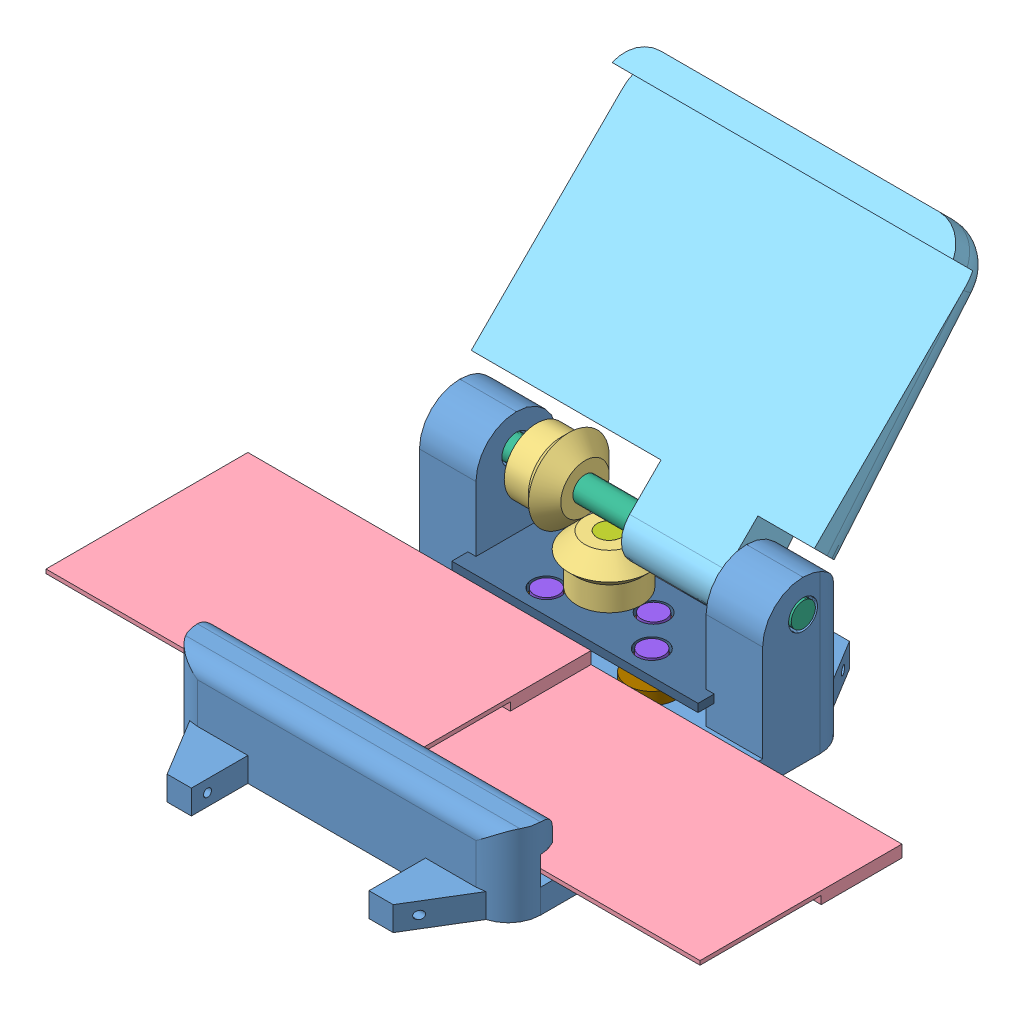
SolidWorks assembly Smartwatch, configuration Default. Lengths in mm.
Overall size (81 46.78 71.64).
16 component instances, 10 part files, 22 mates.
Components (placement in the parent):
- Smartwatch-1: Smartwatch [Default] at (13.8199 22.4056 51.5358) size (42.5 20 56.5)
- Spur Gear 6mm-1: Spur Gear 6mm [Default] at (12.5913 25.4056 31.2058) size (6 3 6)
- Bevel Gear 8mm-2: Bevel Gear 8mm [Default] at (12.5913 29.4056 31.2058) size (10 6 10)
- Bevel Gear 8mm-5: Bevel Gear 8mm [Default] at (3.5913 38.4056 31.2058) x (0 -1 0) z (0 0 1) size (10 6 10)
- Spur Gear 6mm-3: Spur Gear 6mm [Default] at (18.0913 25.4056 31.2058) size (6 3 6)
- Gear Rack-1: Gear Rack [Default] at (108.5211 25.4056 51.6025) size (42.5 1.5 25)
- Gear Rack-3: Gear Rack [Default] at (70.0211 26.9056 51.6025) size (42.5 1.5 25)
- Lid-1: Lid [Default] at (12.9546 56.2841 18.2771) x (1 0 0) z (0 0.707107 -0.707107) size (42.65 10.3 40)
- Main Shaft-2: Main Shaft [Default] at (36.6296 38.4056 31.2058) x (0 1 0) z (0 0 1) size (3 42.5 3)
- Bevel Axle-1: Bevel Axle [Default] at (12.5913 22.4056 31.2058) size (3 13 3)
- Spur Axle-1: Spur Axle [Default] at (18.0913 22.4056 31.2058) size (3 7 3)
- Spur Axle-2: Spur Axle [Default] at (21.8662 22.4056 35.2058) size (3 7 3)
- Spur Axle-3: Spur Axle [Default] at (8.8164 22.3849 35.2058) size (3 7 3)
- Spur Gear 6mm Low Profile-1: Spur Gear 6mm Low Profile [Default] at (8.7606 26.8735 35.4151) size (6 1.5 6)
- Spur Gear 6mm Low Profile-3: Spur Gear 6mm Low Profile [Default] at (21.8662 25.4056 35.2058) size (6 1.5 6)
- Gear Plate-2: Gear Plate [Default] at (18.4863 28.3735 35.3413) size (30.5 1 11)
Mates (geometry in assembly coordinates):
- Concentric1: concentric: circle of Smartwatch-1; circle of Spur Gear 6mm-1
- Coincident1: coincident: plane of Smartwatch-1 through (13.8199 25.4056 51.5358) normal (0 1 0); plane of Spur Gear 6mm-1 through (12.5913 25.4056 31.2058) normal (0 -1 0)
- Concentric4: concentric: circle of Spur Gear 6mm-1; circle of Bevel Gear 8mm-2
- Perpendicular2: perpendicular: cone of Bevel Gear 8mm-2 through (12.5913 35.4056 31.2058) axis (0 1 0); cone of Bevel Gear 8mm-5 through (9.5913 38.4056 31.2058) axis (1 0 0)
- Tangent4: tangent: circle of Bevel Gear 8mm-2; circle of Bevel Gear 8mm-5
- Perpendicular4: perpendicular: plane of Smartwatch-1 through (4.3413 25.4056 25.2058) normal (0 0 -1); plane of Bevel Gear 8mm-5 through (3.5913 38.4056 31.2058) normal (-1 0 0)
- Coincident21: coincident: plane of Smartwatch-1 through (13.8199 25.4056 51.5358) normal (0 1 0); plane of Spur Gear 6mm-3 through (18.0913 25.4056 31.2058) normal (0 -1 0)
- Coincident23: coincident: plane of Smartwatch-1 through (13.8199 25.4056 51.5358) normal (0 1 0); plane of Gear Rack-1 through (108.5211 25.4056 51.6025) normal (0 -1 0)
- Coincident26: coincident: plane of Gear Rack-1 through (108.5211 26.9056 51.6025) normal (0 1 0); plane of Gear Rack-3 through (70.0211 26.9056 51.6025) normal (0 -1 0)
- Distance1: distance = 2 mm: moEndPointRef_w of Smartwatch-1; plane of Gear Rack-1 through (13.3413 26.4056 38.2058) normal (-1 0 0)
- Distance2: distance = 2 mm: moEndPointRef_w of Smartwatch-1; plane of Gear Rack-3 through (17.3413 27.9056 38.2058) normal (1 0 0)
- Coincident30: coincident: circle of Smartwatch-1; circle of Lid-1
- Coincident31: coincident: plane of Smartwatch-1 through (29.5913 42.4056 26.2058) normal (-1 0 0); plane of Lid-1 through (29.5913 39.8198 24.8419) normal (1 0 0)
- Concentric9: concentric: circle of Smartwatch-1; circle of Main Shaft-2
- Coincident35: coincident: circle of Bevel Gear 8mm-2; circle of Bevel Axle-1
- Coincident42: coincident: plane of Smartwatch-1 through (13.8199 25.4056 51.5358) normal (0 1 0); circle of Spur Gear 6mm Low Profile-3
- Coincident46: coincident: plane of Smartwatch-1 through (13.8199 22.4056 51.5358) normal (0 -1 0); plane of Spur Axle-2 through (21.8662 22.4056 35.2058) normal (0 -1 0)
- Concentric13: concentric: circle of Smartwatch-1; circle of Spur Axle-2
- Coincident52: coincident: plane of Smartwatch-1 through (13.8199 22.4056 51.5358) normal (0 -1 0); plane of Bevel Axle-1 through (12.5913 22.4056 31.2058) normal (0 -1 0)
- Concentric14: concentric: circle of Smartwatch-1; circle of Spur Axle-3
- Concentric17: concentric: circle of Smartwatch-1; circle of Spur Axle-1
- Coincident55: coincident: point of Smartwatch-1; point of Gear Plate-2
